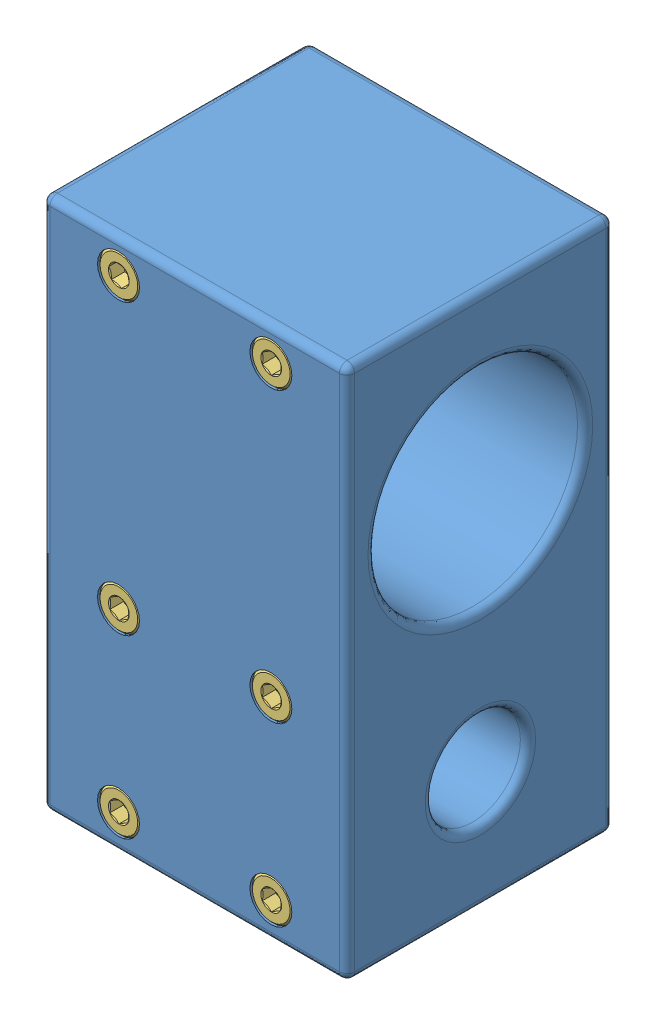
SolidWorks assembly bikemountassembly, configuration Default. Lengths in mm.
Overall size (50.8 88.9 44.54).
13 component instances, 3 part files, 29 mates.
Components (placement in the parent):
- bikelockmount-1: bikelockmount [Default] at (-20.6321 23.671 112.0733) size (50.8 88.9 44.45)
- 90695A035_Steel Thin Hex Nut-1: 90695A035_Steel Thin Hex Nut [90695A035] at (-7.9321 58.9135 69.0633) x (0.866025 -0.5 0) z (0 0 1) size (7 8.08 2.5)
- 91292A132_18-8 Stainless Steel Socket Head Screw-1: 91292A132_18-8 Stainless Steel Socket Head Screw [91292A132] at (-7.9321 58.9135 90.0093) size (7 7 44.47)
- 91292A132_18-8 Stainless Steel Socket Head Screw-2: 91292A132_18-8 Stainless Steel Socket Head Screw [91292A132] at (17.4679 107.0148 90.0093) size (7 7 44.47)
- 91292A132_18-8 Stainless Steel Socket Head Screw-3: 91292A132_18-8 Stainless Steel Socket Head Screw [91292A132] at (-7.9321 107.0148 90.0093) x (0.968481 0.249087 0) z (0 0 1) size (7 7 44.47)
- 91292A132_18-8 Stainless Steel Socket Head Screw-4: 91292A132_18-8 Stainless Steel Socket Head Screw [91292A132] at (-7.9321 29.5448 90.0093) size (7 7 44.47)
- 91292A132_18-8 Stainless Steel Socket Head Screw-5: 91292A132_18-8 Stainless Steel Socket Head Screw [91292A132] at (17.4679 58.9135 90.0093) size (7 7 44.47)
- 91292A132_18-8 Stainless Steel Socket Head Screw-6: 91292A132_18-8 Stainless Steel Socket Head Screw [91292A132] at (17.4679 29.5448 90.0093) size (7 7 44.47)
- 90695A035_Steel Thin Hex Nut-2: 90695A035_Steel Thin Hex Nut [90695A035] at (17.4679 107.0148 69.0633) x (0.866025 -0.5 0) z (0 0 1) size (7 8.08 2.5)
- 90695A035_Steel Thin Hex Nut-3: 90695A035_Steel Thin Hex Nut [90695A035] at (-7.9321 29.5448 69.0633) x (0.866025 -0.5 0) z (0 0 1) size (7 8.08 2.5)
- 90695A035_Steel Thin Hex Nut-4: 90695A035_Steel Thin Hex Nut [90695A035] at (17.4679 29.5448 69.0633) x (0.866025 -0.5 0) z (0 0 1) size (7 8.08 2.5)
- 90695A035_Steel Thin Hex Nut-5: 90695A035_Steel Thin Hex Nut [90695A035] at (17.4679 58.9135 69.0633) x (0.925259 0.379336 0) z (0 0 1) size (7 8.08 2.5)
- 90695A035_Steel Thin Hex Nut-6: 90695A035_Steel Thin Hex Nut [90695A035] at (-7.9321 107.0148 69.0633) x (0 1 0) z (0 0 -1) size (7 8.08 2.5)
Mates (geometry in assembly coordinates):
- Concentric1: concentric aligned: circle of bikelockmount-1; cylinder of 91292A132_18-8 Stainless Steel Socket Head Screw-3 through (-7.9321 107.0148 68.0093) axis (0 0 -1) radius 2
- Concentric2: concentric anti-aligned: cylinder of bikelockmount-1 through (17.4679 107.0148 67.6233) axis (0 0 1) radius 2.032; cylinder of 91292A132_18-8 Stainless Steel Socket Head Screw-2 through (17.4679 107.0148 68.0093) axis (0 0 -1) radius 2
- Concentric3: concentric anti-aligned: cylinder of bikelockmount-1 through (-7.9321 58.9135 67.6233) axis (0 0 1) radius 2.032; cylinder of 91292A132_18-8 Stainless Steel Socket Head Screw-1 through (-7.9321 58.9135 68.0093) axis (0 0 -1) radius 2
- Concentric4: concentric anti-aligned: cylinder of bikelockmount-1 through (17.4679 58.9135 67.6233) axis (0 0 1) radius 2.032; cylinder of 91292A132_18-8 Stainless Steel Socket Head Screw-5 through (17.4679 58.9135 68.0093) axis (0 0 -1) radius 2
- Concentric5: concentric anti-aligned: cylinder of bikelockmount-1 through (-7.9321 29.5448 67.6233) axis (0 0 1) radius 2.032; cylinder of 91292A132_18-8 Stainless Steel Socket Head Screw-4 through (-7.9321 29.5448 68.0093) axis (0 0 -1) radius 2
- Concentric6: concentric anti-aligned: cylinder of bikelockmount-1 through (17.4679 29.5448 67.6233) axis (0 0 1) radius 2.032; cylinder of 91292A132_18-8 Stainless Steel Socket Head Screw-6 through (17.4679 29.5448 68.0093) axis (0 0 -1) radius 2
- Coincident1: coincident anti-aligned: plane of bikelockmount-1 through (-7.9321 107.0148 108.0093) normal (0 0 1); plane of 91292A132_18-8 Stainless Steel Socket Head Screw-3 through (-11.1523 106.1866 108.0093) normal (0 0 -1)
- Coincident2: coincident anti-aligned: plane of bikelockmount-1 through (17.4679 107.0148 108.0093) normal (0 0 1); plane of 91292A132_18-8 Stainless Steel Socket Head Screw-2 through (14.1429 107.0148 108.0093) normal (0 0 -1)
- Coincident3: coincident anti-aligned: plane of bikelockmount-1 through (-7.9321 58.9135 108.0093) normal (0 0 1); plane of 91292A132_18-8 Stainless Steel Socket Head Screw-1 through (-11.2571 58.9135 108.0093) normal (0 0 -1)
- Coincident4: coincident anti-aligned: plane of bikelockmount-1 through (17.4679 58.9135 108.0093) normal (0 0 1); plane of 91292A132_18-8 Stainless Steel Socket Head Screw-5 through (14.1429 58.9135 108.0093) normal (0 0 -1)
- Coincident5: coincident anti-aligned: plane of bikelockmount-1 through (17.4679 29.5448 108.0093) normal (0 0 1); plane of 91292A132_18-8 Stainless Steel Socket Head Screw-6 through (14.1429 29.5448 108.0093) normal (0 0 -1)
- Coincident6: coincident anti-aligned: plane of bikelockmount-1 through (-7.9321 29.5448 108.0093) normal (0 0 1); plane of 91292A132_18-8 Stainless Steel Socket Head Screw-4 through (-11.2571 29.5448 108.0093) normal (0 0 -1)
- Concentric9: concentric anti-aligned: circle of bikelockmount-1; circle of 90695A035_Steel Thin Hex Nut-6
- Parallel3: parallel aligned: plane of 90695A035_Steel Thin Hex Nut-6 through (-9.9529 110.5148 67.9633) normal (0 1 0)
- Parallel4: parallel aligned: plane of 90695A035_Steel Thin Hex Nut-4 through (19.4886 33.0448 70.1633) normal (0 1 0); plane of 90695A035_Steel Thin Hex Nut-6 through (-9.9529 110.5148 67.9633) normal (0 1 0)
- Parallel5: parallel aligned: plane of 90695A035_Steel Thin Hex Nut-1 through (-5.9114 62.4135 70.1633) normal (0 1 0); plane of 90695A035_Steel Thin Hex Nut-6 through (-9.9529 110.5148 67.9633) normal (0 1 0)
- Parallel6: parallel aligned: plane of 90695A035_Steel Thin Hex Nut-3 through (-5.9114 33.0448 70.1633) normal (0 1 0); plane of 90695A035_Steel Thin Hex Nut-6 through (-9.9529 110.5148 67.9633) normal (0 1 0)
- Parallel7: parallel aligned: plane of 90695A035_Steel Thin Hex Nut-2 through (19.4886 110.5148 70.1633) normal (0 1 0); plane of 90695A035_Steel Thin Hex Nut-6 through (-9.9529 110.5148 67.9633) normal (0 1 0)
- Concentric10: concentric aligned: circle of bikelockmount-1; circle of 90695A035_Steel Thin Hex Nut-2
- Concentric11: concentric aligned: circle of bikelockmount-1; circle of 90695A035_Steel Thin Hex Nut-1
- Concentric14: concentric: circle of bikelockmount-1; circle of 90695A035_Steel Thin Hex Nut-5
- Concentric16: concentric aligned: circle of bikelockmount-1; circle of 90695A035_Steel Thin Hex Nut-3
- Concentric17: concentric aligned: circle of bikelockmount-1; circle of 90695A035_Steel Thin Hex Nut-4
- Coincident17: coincident anti-aligned: plane of bikelockmount-1 through (-20.6321 23.671 70.1633) normal (0 0 -1); plane of 90695A035_Steel Thin Hex Nut-1 through (-7.9321 58.9135 70.1633) normal (0 0 1)
- Coincident18: coincident anti-aligned: plane of bikelockmount-1 through (-20.6321 23.671 70.1633) normal (0 0 -1); plane of 90695A035_Steel Thin Hex Nut-5 through (17.4679 58.9135 70.1633) normal (0 0 1)
- Coincident19: coincident anti-aligned: plane of bikelockmount-1 through (-20.6321 23.671 70.1633) normal (0 0 -1); plane of 90695A035_Steel Thin Hex Nut-3 through (-7.9321 29.5448 70.1633) normal (0 0 1)
- Coincident20: coincident anti-aligned: plane of bikelockmount-1 through (-20.6321 23.671 70.1633) normal (0 0 -1); plane of 90695A035_Steel Thin Hex Nut-4 through (17.4679 29.5448 70.1633) normal (0 0 1)
- Coincident21: coincident anti-aligned: plane of bikelockmount-1 through (-20.6321 23.671 70.1633) normal (0 0 -1); plane of 90695A035_Steel Thin Hex Nut-6 through (-7.9321 107.0148 70.1633) normal (0 0 1)
- Coincident22: coincident anti-aligned: plane of bikelockmount-1 through (-20.6321 23.671 70.1633) normal (0 0 -1); plane of 90695A035_Steel Thin Hex Nut-2 through (17.4679 107.0148 70.1633) normal (0 0 1)
